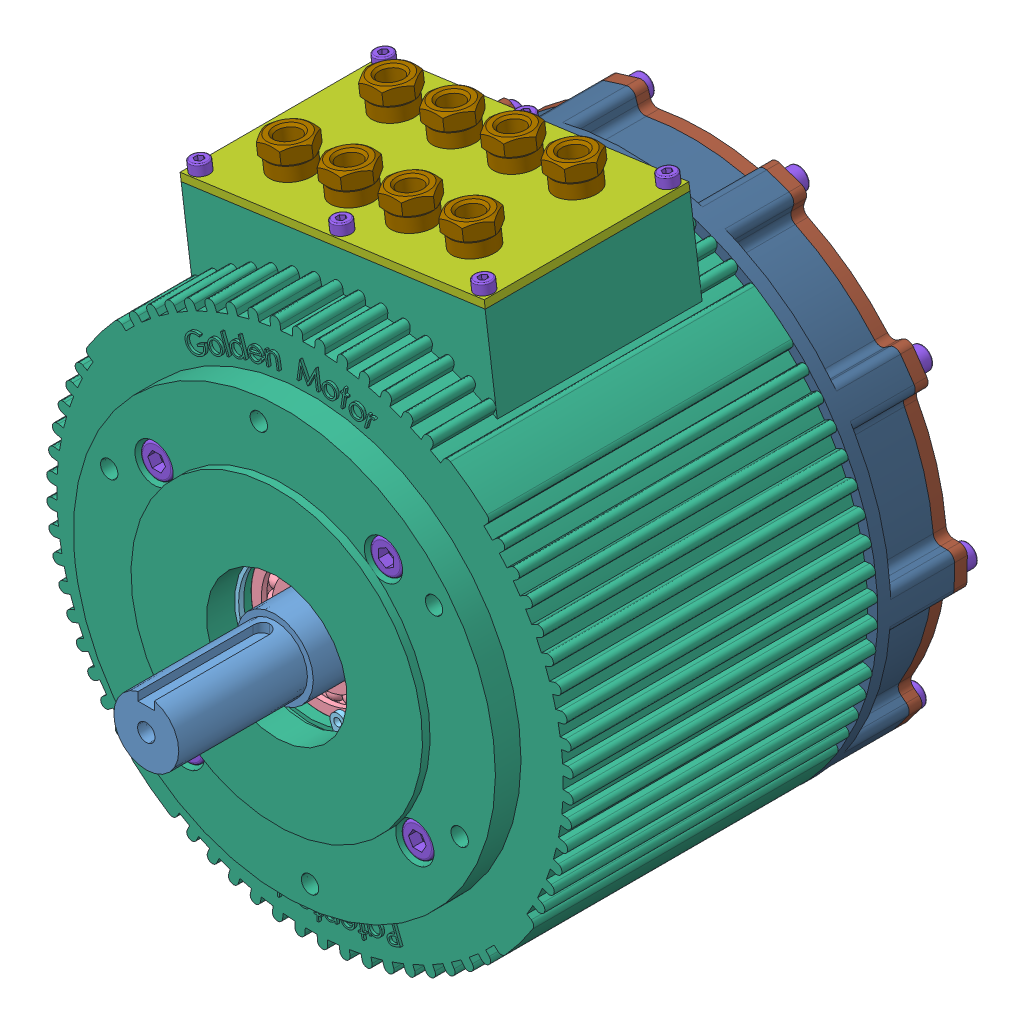
SolidWorks assembly （外形图）水冷图, configuration 默认. Lengths in mm.
Overall size (288.65 288.65 226).
44 component instances, 11 part files, 30 mates.
Components (placement in the parent):
- 轴-1: 轴 [默认] at (4.5506 0 -103.5) size (35 35 206.3)
- Hexagon socket button head screws GB-1: Hexagon socket button head screws GB [GB_SOCKET_TYPE7 M4X8-N] at (-6.919 -27.7209 -32.7) x (0 0 1) z (0.923728 0.383049 0) size (10.2 7.6 7.6)
- Hexagon socket button head screws GB-2: Hexagon socket button head screws GB [GB_SOCKET_TYPE7 M4X8-N] at (-6.9409 27.7118 -16.3) x (0 0 -1) z (1 0 0) size (10.2 7.6 7.6)
- Circlips for shaft--Type A large GB-1: Circlips for shaft--Type A large GB [GB_CONNECTING_PIECE_RING_RRA 30] at (4.3214 0.9013 -39.6) x (0.969151 0.246466 0) z (0 0 1) size (33.5 36.57 1.2)
- Deep groove ball bearings GB-1: Deep groove ball bearings GB [Rolling bearings 16006 GB 276-94] at (4.5506 0 30) x (0 0 1) z (0.923728 0.383049 0) size (9 55 55)
- Deep groove ball bearings GB-2: Deep groove ball bearings GB [Rolling bearings 6205 GB 276-94] at (4.5506 0 -72) x (0 0 1) z (-1 0 0) size (15 52 52)
- Circlips for holes--Type A GB-1: Circlips for holes--Type A GB [GB_CONNECTING_PIECE_RING_RRH 52] at (5.0102 -1.1085 -81.5) x (0.923728 0.383049 0) z (0 0 -1) size (56.2 54.06 2)
- 机壳-1: 机壳 [默认] at (4.5506 0 51.8) x (-0.990795 -0.135368 0) z (0 0 -1) size (206 217 132)
- 出线板-1: 出线板 [默认] at (-6.2623 113.5818 -4.2972) x (0.990795 0.135368 0) z (-0.135368 0.990795 0) size (120 80 3)
- Hexagon socket head cap screws GB-1: Hexagon socket head cap screws GB [GB_FASTENER_SCREWS_HSHCS M5X16-N] at (-23.7416 93.8272 -120.2) x (0 0 1) z (-1 0 0) size (21 8.5 8.5)
- Hexagon socket head cap screws GB-2: Hexagon socket head cap screws GB [GB_FASTENER_SCREWS_HSHCS M8X16-N] at (57.1169 36.5072 -123.2) x (0 0 1) z (-1 0 0) size (24 13 13)
- Hexagon socket head cap screws GB-3: Hexagon socket head cap screws GB [GB_FASTENER_SCREWS_HSHCS M8X20-N] at (-46.4138 38.7122 47.8) x (0 0 -1) z (1 0 0) size (28 13 13)
- Prevailing torque type 1 with fine pitch GB-1: Prevailing torque type 1 with fine pitch GB [GB_HEXAGON_TYPE11 M10X1-N] at (-47.654 116.1578 -45.7) x (0.497865 0.068021 -0.864583) z (0.135368 -0.990795 0) size (18.48 16 11.9)
- Hexagon socket head cap screws GB-5: Hexagon socket head cap screws GB [GB_FASTENER_SCREWS_HSHCS M8X20-N] at (43.2628 50.9643 47.8) x (0 0 -1) z (0 -1 0) size (28 13 13)
- Hexagon socket head cap screws GB-6: Hexagon socket head cap screws GB [GB_FASTENER_SCREWS_HSHCS M8X20-N] at (55.5149 -38.7122 47.8) x (0 0 -1) z (-1 0 0) size (28 13 13)
- Hexagon socket head cap screws GB-7: Hexagon socket head cap screws GB [GB_FASTENER_SCREWS_HSHCS M8X20-N] at (-34.1616 -50.9643 47.8) x (0 0 -1) z (0 1 0) size (28 13 13)
- Circlips for holes--Type A GB-2: Circlips for holes--Type A GB [GB_CONNECTING_PIECE_RING_RRH 55] at (4.5506 1.2 40.6) size (59.2 56.95 2)
- Prevailing torque type 1 with fine pitch GB-2: Prevailing torque type 1 with fine pitch GB [GB_HEXAGON_TYPE11 M10X1-N] at (-47.654 116.1578 -5.7) x (0.497865 0.068021 -0.864583) z (0.135368 -0.990795 0) size (18.48 16 11.9)
- Prevailing torque type 1 with fine pitch GB-3: Prevailing torque type 1 with fine pitch GB [GB_HEXAGON_TYPE11 M10X1-N] at (-23.8749 119.4066 -45.7) x (0.497865 0.068021 -0.864583) z (0.135368 -0.990795 0) size (18.48 16 11.9)
- Prevailing torque type 1 with fine pitch GB-4: Prevailing torque type 1 with fine pitch GB [GB_HEXAGON_TYPE11 M10X1-N] at (-23.8749 119.4066 -5.7) x (0.497865 0.068021 -0.864583) z (0.135368 -0.990795 0) size (18.48 16 11.9)
- Prevailing torque type 1 with fine pitch GB-5: Prevailing torque type 1 with fine pitch GB [GB_HEXAGON_TYPE11 M10X1-N] at (-0.0958 122.6554 -45.7) x (0.497865 0.068021 -0.864583) z (0.135368 -0.990795 0) size (18.48 16 11.9)
- Prevailing torque type 1 with fine pitch GB-6: Prevailing torque type 1 with fine pitch GB [GB_HEXAGON_TYPE11 M10X1-N] at (-0.0958 122.6554 -5.7) x (0.497865 0.068021 -0.864583) z (0.135368 -0.990795 0) size (18.48 16 11.9)
- Prevailing torque type 1 with fine pitch GB-7: Prevailing torque type 1 with fine pitch GB [GB_HEXAGON_TYPE11 M10X1-N] at (23.6833 125.9043 -45.7) x (0.497865 0.068021 -0.864583) z (0.135368 -0.990795 0) size (18.48 16 11.9)
- Prevailing torque type 1 with fine pitch GB-8: Prevailing torque type 1 with fine pitch GB [GB_HEXAGON_TYPE11 M10X1-N] at (23.6833 125.9043 -5.7) x (0.497865 0.068021 -0.864583) z (0.135368 -0.990795 0) size (18.48 16 11.9)
- Hexagon socket head cap screws GB-14: Hexagon socket head cap screws GB [GB_FASTENER_SCREWS_HSHCS M4X10-N] at (-67.3135 112.3056 10.3) x (0.135368 -0.990795 0) z (0 0 1) size (14 7 7)
- Hexagon socket head cap screws GB-15: Hexagon socket head cap screws GB [GB_FASTENER_SCREWS_HSHCS M4X10-N] at (-67.3135 112.3056 -61.7) x (0.135368 -0.990795 0) z (0 0 1) size (14 7 7)
- Hexagon socket head cap screws GB-16: Hexagon socket head cap screws GB [GB_FASTENER_SCREWS_HSHCS M4X10-N] at (-11.829 119.8862 10.3) x (0.135368 -0.990795 0) z (0 0 1) size (14 7 7)
- Hexagon socket head cap screws GB-17: Hexagon socket head cap screws GB [GB_FASTENER_SCREWS_HSHCS M4X10-N] at (-11.829 119.8862 -61.7) x (0.135368 -0.990795 0) z (0 0 1) size (14 7 7)
- Hexagon socket head cap screws GB-18: Hexagon socket head cap screws GB [GB_FASTENER_SCREWS_HSHCS M4X10-N] at (43.6556 127.4669 10.3) x (0.135368 -0.990795 0) z (0 0 1) size (14 7 7)
- Hexagon socket head cap screws GB-19: Hexagon socket head cap screws GB [GB_FASTENER_SCREWS_HSHCS M4X10-N] at (43.6556 127.4669 -61.7) x (0.135368 -0.990795 0) z (0 0 1) size (14 7 7)
- 水冷盖-1: 水冷盖 [默认] at (4.5506 0 -61) x (0 0 -1) z (0.796318 -0.604878 0) size (49.2 206 206)
- 水冷盖板-1: 水冷盖板 [默认] at (4.5506 0 -110.2) x (0.570426 -0.821349 0) z (0 0 -1) size (198.8 206 5)
- Hexagon socket head cap screws GB-23: Hexagon socket head cap screws GB [GB_FASTENER_SCREWS_HSHCS M5X16-N] at (-73.4886 59.2781 -120.2) x (0 0 1) z (-0.809017 -0.587785 0) size (21 8.5 8.5)
- Hexagon socket head cap screws GB-24: Hexagon socket head cap screws GB [GB_FASTENER_SCREWS_HSHCS M5X16-N] at (-93.4272 2.0867 -120.2) x (0 0 1) z (-0.309017 -0.951057 0) size (21 8.5 8.5)
- Hexagon socket head cap screws GB-25: Hexagon socket head cap screws GB [GB_FASTENER_SCREWS_HSHCS M5X16-N] at (-75.9416 -55.9017 -120.2) x (0 0 1) z (0.309017 -0.951057 0) size (21 8.5 8.5)
- Hexagon socket head cap screws GB-26: Hexagon socket head cap screws GB [GB_FASTENER_SCREWS_HSHCS M5X16-N] at (-27.7108 -92.5376 -120.2) x (0 0 1) z (0.809017 -0.587785 0) size (21 8.5 8.5)
- Hexagon socket head cap screws GB-27: Hexagon socket head cap screws GB [GB_FASTENER_SCREWS_HSHCS M5X16-N] at (32.8428 -93.8272 -120.2) x (0 0 1) z (1 0 0) size (21 8.5 8.5)
- Hexagon socket head cap screws GB-28: Hexagon socket head cap screws GB [GB_FASTENER_SCREWS_HSHCS M5X16-N] at (82.5897 -59.2781 -120.2) x (0 0 1) z (0.809017 0.587785 0) size (21 8.5 8.5)
- Hexagon socket head cap screws GB-29: Hexagon socket head cap screws GB [GB_FASTENER_SCREWS_HSHCS M5X16-N] at (102.5284 -2.0867 -120.2) x (0 0 1) z (0.309017 0.951057 0) size (21 8.5 8.5)
- Hexagon socket head cap screws GB-30: Hexagon socket head cap screws GB [GB_FASTENER_SCREWS_HSHCS M5X16-N] at (85.0428 55.9017 -120.2) x (0 0 1) z (-0.309017 0.951057 0) size (21 8.5 8.5)
- Hexagon socket head cap screws GB-31: Hexagon socket head cap screws GB [GB_FASTENER_SCREWS_HSHCS M5X16-N] at (36.812 92.5376 -120.2) x (0 0 1) z (-0.809017 0.587785 0) size (21 8.5 8.5)
- Hexagon socket head cap screws GB-32: Hexagon socket head cap screws GB [GB_FASTENER_SCREWS_HSHCS M8X16-N] at (-31.9567 52.5664 -123.2) x (0 0 1) z (0 -1 0) size (24 13 13)
- Hexagon socket head cap screws GB-33: Hexagon socket head cap screws GB [GB_FASTENER_SCREWS_HSHCS M8X16-N] at (-48.0158 -36.5072 -123.2) x (0 0 1) z (1 0 0) size (24 13 13)
- Hexagon socket head cap screws GB-34: Hexagon socket head cap screws GB [GB_FASTENER_SCREWS_HSHCS M8X16-N] at (41.0578 -52.5664 -123.2) x (0 0 1) z (0 1 0) size (24 13 13)
Mates (geometry in assembly coordinates):
- 同心8: concentric anti-aligned: circle of 轴-1; circle of Circlips for shaft--Type A large GB-1
- 重合6: coincident anti-aligned: circle of 轴-1; plane of Circlips for shaft--Type A large GB-1 through (4.5506 0 -40.8) normal (0 0 -1)
- 同心11: concentric anti-aligned: circle of 轴-1; circle of Deep groove ball bearings GB-2
- 重合10: coincident aligned: circle of 轴-1; plane of Deep groove ball bearings GB-2 through (4.5506 12.5 -64.5) normal (0 0 1)
- 同心12: concentric aligned: circle of 轴-1; circle of Deep groove ball bearings GB-1
- 重合11: coincident anti-aligned: plane of 轴-1 through (4.5506 0 25.5) normal (0 0 1); plane of Deep groove ball bearings GB-1 through (15.0844 -25.4025 25.5) normal (0 0 -1)
- 同心15: concentric aligned: circle of 轴-1; circle of Circlips for holes--Type A GB-1
- 重合36: coincident anti-aligned: plane of 机壳-1 through (-70.3291 104.8286 14.3) normal (-0.135368 0.990795 0); plane of 出线板-1 through (-70.3291 104.8286 14.3) normal (0.135368 -0.990795 0)
- 重合37: coincident aligned: plane of 机壳-1 through (-40.9541 -110.175 14.3) normal (-0.990795 -0.135368 0); plane of 出线板-1 through (-70.7352 107.801 -65.7) normal (-0.990795 -0.135368 0)
- 重合38: coincident aligned: plane of 机壳-1 through (-40.9541 -110.175 -65.7) normal (0 0 -1); plane of 出线板-1 through (-70.7352 107.801 -65.7) normal (0 0 -1)
- 同心30: concentric anti-aligned: circle of 机壳-1; circle of Hexagon socket head cap screws GB-3
- 重合40: coincident anti-aligned: plane of 机壳-1 through (-51.3677 38.0354 39.8) normal (0 0 1); circle of Hexagon socket head cap screws GB-3
- 同心37: concentric aligned: circle of 机壳-1; circle of Circlips for holes--Type A GB-2
- 重合45: coincident anti-aligned: plane of 机壳-1 through (4.5506 0 38.6) normal (0 0 1); circle of Circlips for holes--Type A GB-2
- 同心38: concentric anti-aligned: circle of 出线板-1; circle of Prevailing torque type 1 with fine pitch GB-1
- 重合46: coincident aligned: plane of 出线板-1 through (-70.7352 107.801 14.3) normal (-0.135368 0.990795 0); circle of Prevailing torque type 1 with fine pitch GB-1
- 同心39: concentric anti-aligned: circle of 出线板-1; circle of Hexagon socket head cap screws GB-14
- 重合47: coincident anti-aligned: plane of 出线板-1 through (-70.7352 107.801 14.3) normal (-0.135368 0.990795 0); circle of Hexagon socket head cap screws GB-14
- 同心47: concentric anti-aligned: circle of 机壳-1; circle of 水冷盖-1
- 重合53: coincident anti-aligned: circle of 机壳-1; plane of 水冷盖-1 through (60.8043 74.0576 -80.2) normal (0 0 1)
- 同心51: concentric anti-aligned: circle of 水冷盖-1; circle of 水冷盖板-1
- 重合54: coincident anti-aligned: plane of 水冷盖-1 through (66.8531 82.0207 -110.2) normal (0 0 -1); plane of 水冷盖板-1 through (-74.9342 -60.6808 -110.2) normal (0 0 1)
- 同心53: concentric aligned: circle of 水冷盖-1; circle of 水冷盖板-1
- 同心54: concentric anti-aligned: circle of Hexagon socket head cap screws GB-1; circle of 水冷盖板-1
- 重合55: coincident anti-aligned: circle of Hexagon socket head cap screws GB-1; plane of 水冷盖板-1 through (-74.9342 -60.6808 -115.2) normal (0 0 -1)
- 同心55: concentric anti-aligned: circle of Hexagon socket head cap screws GB-2; circle of 水冷盖板-1
- 重合56: coincident anti-aligned: circle of Hexagon socket head cap screws GB-2; plane of 水冷盖板-1 through (-74.9342 -60.6808 -115.2) normal (0 0 -1)
- 局部线性阵列2: unknown: line of 出线板-1 through (-70.7352 107.801 14.3) axis (0.990795 0.135368 0); line of 出线板-1 through (-70.7352 107.801 -65.7) axis (0 0 1)
- 局部圆周阵列10: unknown: line of 水冷盖-1 through (4.5506 0 -80.2) axis (0 0 1)
- 局部圆周阵列11: unknown: line of 水冷盖-1 through (4.5506 0 -80.2) axis (0 0 1)
